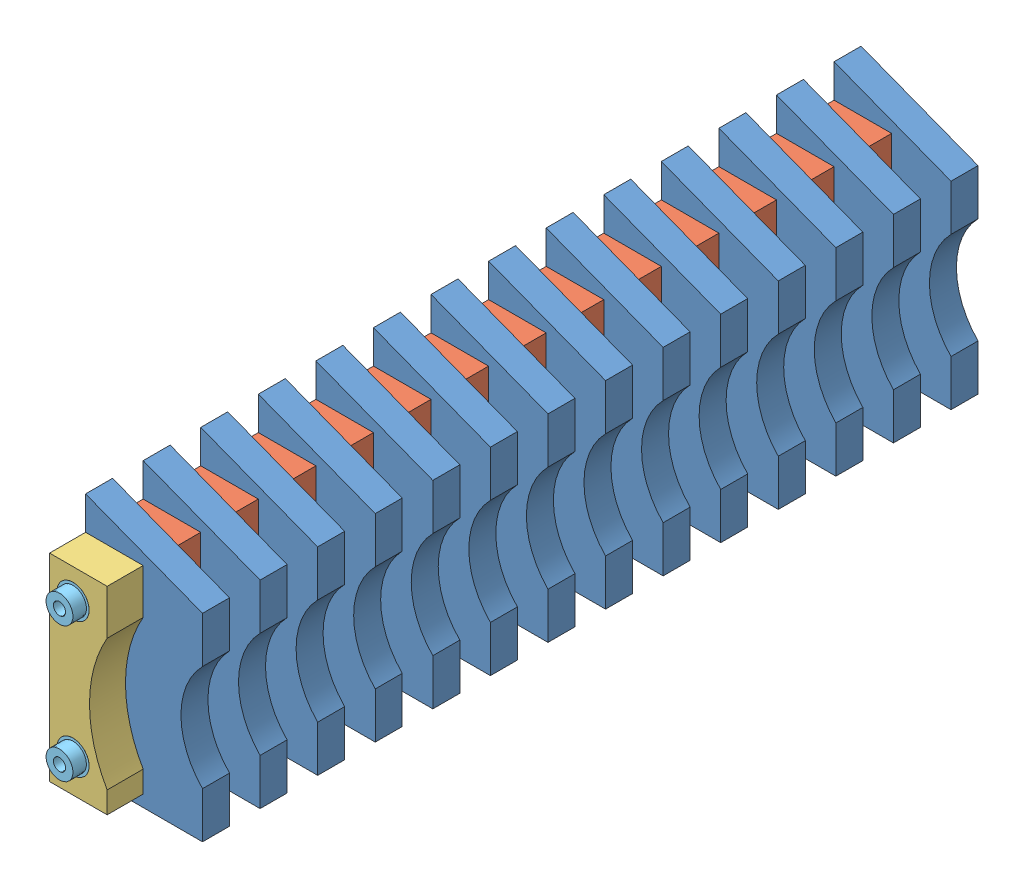
SolidWorks assembly KR.10.06, configuration Default. Lengths in mm.
Overall size (65 135 470).
31 component instances, 5 part files, 12 mates.
Components (placement in the parent):
- KR.12.04-1: KR.12.04 [Default] at (40.0493 6.8509 89.2819) size (65 135 15)
- KR.12.04-2: KR.12.04 [Default] at (40.0493 6.8509 121.2819) size (65 135 15)
- KR.12.04-3: KR.12.04 [Default] at (40.0493 6.8509 153.2819) size (65 135 15)
- KR.12.04-4: KR.12.04 [Default] at (40.0493 6.8509 185.2819) size (65 135 15)
- KR.12.04-5: KR.12.04 [Default] at (40.0493 6.8509 217.2819) size (65 135 15)
- KR.12.04-6: KR.12.04 [Default] at (40.0493 6.8509 249.2819) size (65 135 15)
- KR.12.04-7: KR.12.04 [Default] at (40.0493 6.8509 281.2819) size (65 135 15)
- KR.12.04-8: KR.12.04 [Default] at (40.0493 6.8509 313.2819) size (65 135 15)
- KR.12.04-9: KR.12.04 [Default] at (40.0493 6.8509 345.2819) size (65 135 15)
- KR.12.04-10: KR.12.04 [Default] at (40.0493 6.8509 377.2819) size (65 135 15)
- KR.12.04-11: KR.12.04 [Default] at (40.0493 6.8509 409.2819) size (65 135 15)
- KR.12.04-12: KR.12.04 [Default] at (40.0493 6.8509 441.2819) size (65 135 15)
- KR.12.04-13: KR.12.04 [Default] at (40.0493 6.8509 473.2819) size (65 135 15)
- KR.12.04-14: KR.12.04 [Default] at (40.0493 6.8509 505.2819) size (65 135 15)
- KR.13.09-1: KR.13.09 [Default] at (40.0493 13.3509 105.2819) size (32 110 17)
- KR.13.09-2: KR.13.09 [Default] at (40.0493 13.3509 137.2819) size (32 110 17)
- KR.13.09-3: KR.13.09 [Default] at (40.0493 13.3509 169.2819) size (32 110 17)
- KR.13.09-4: KR.13.09 [Default] at (40.0493 13.3509 201.2819) size (32 110 17)
- KR.13.09-5: KR.13.09 [Default] at (40.0493 13.3509 233.2819) size (32 110 17)
- KR.13.09-6: KR.13.09 [Default] at (40.0493 13.3509 265.2819) size (32 110 17)
- KR.13.09-7: KR.13.09 [Default] at (40.0493 13.3509 297.2819) size (32 110 17)
- KR.13.09-8: KR.13.09 [Default] at (40.0493 13.3509 329.2819) size (32 110 17)
- KR.13.09-9: KR.13.09 [Default] at (40.0493 13.3509 361.2819) size (32 110 17)
- KR.13.09-10: KR.13.09 [Default] at (40.0493 13.3509 393.2819) size (32 110 17)
- KR.13.09-11: KR.13.09 [Default] at (40.0493 13.3509 425.2819) size (32 110 17)
- KR.13.09-12: KR.13.09 [Default] at (40.0493 13.3509 457.2819) size (32 110 17)
- KR.13.09-13: KR.13.09 [Default] at (40.0493 13.3509 489.2819) size (32 110 17)
- KR.13.11-1: KR.13.11 [Default] at (40.0493 13.3509 522.7819) size (32 110 20)
- KR.13.12-1: KR.13.12 [Default] at (40.0493 13.3509 79.7819) size (32 110 4)
- KR.13.08-1: KR.13.08 [Default] at (53.0493 31.8509 305.2819) x (0 0 -1) z (0.733858 -0.679303 0) size (470 18 18)
- KR.13.08-2: KR.13.08 [Default] at (53.0493 106.8509 305.2819) x (0 0 -1) z (-0.134257 0.990947 0) size (470 18 18)
Mates (geometry in assembly coordinates):
- Eş Merkezli1: concentric aligned: cylinder of KR.12.04-1 through (53.0493 106.8509 81.7819) axis (0 0 1) radius 9; cylinder of KR.13.09-1 through (53.0493 106.8509 96.7819) axis (0 0 1) radius 9
- Eş Merkezli2: concentric aligned: cylinder of KR.12.04-2 through (53.0493 31.8509 113.7819) axis (0 0 1) radius 9; cylinder of KR.13.09-1 through (53.0493 31.8509 96.7819) axis (0 0 1) radius 9
- Çakışık5: coincident anti-aligned: plane of KR.12.04-1 through (135.0493 61.8509 81.7819) normal (0 0 -1); plane of KR.13.12-1 through (135.0493 61.8509 81.7819) normal (0 0 1)
- Eş Merkezli9: concentric aligned: cylinder of KR.13.12-1 through (53.0493 31.8509 77.7819) axis (0 0 1) radius 9; cylinder of KR.13.08-1 through (53.0493 31.8509 540.2819) axis (0 0 1) radius 9
- Eş Merkezli10: concentric: cylinder of KR.13.12-1 through (53.0493 106.8509 77.7819) axis (0 0 1) radius 9; cylinder of KR.13.08-2 through (53.0493 106.8509 531.4674) axis (0 0 1) radius 9
- Eş Merkezli11: concentric: cylinder of KR.12.04-1 through (53.0493 106.8509 81.7819) axis (0 0 1) radius 9; cylinder of KR.13.08-2 through (53.0493 106.8509 531.4674) axis (0 0 1) radius 9
- Eş Merkezli12: concentric aligned: cylinder of KR.12.04-1 through (53.0493 31.8509 81.7819) axis (0 0 1) radius 9; cylinder of KR.13.08-1 through (53.0493 31.8509 540.2819) axis (0 0 1) radius 9
- Çakışık6: coincident aligned: plane of KR.13.12-1 through (135.0493 61.8509 77.7819) normal (0 0 -1); plane of KR.13.08-1 through (48.1393 24.3083 77.7819) normal (0 0 -1)
- Çakışık7: coincident anti-aligned: plane of KR.12.04-14 through (135.0493 61.8509 512.7819) normal (0 0 1); plane of KR.13.11-1 through (135.0493 61.8509 512.7819) normal (0 0 -1)
- Eş Merkezli13: concentric: cylinder of KR.13.11-1 through (53.0493 106.8509 512.7819) axis (0 0 1) radius 9; cylinder of KR.13.08-2 through (53.0493 106.8509 531.4674) axis (0 0 1) radius 9
- Eş Merkezli14: concentric aligned: cylinder of KR.13.11-1 through (53.0493 31.8509 512.7819) axis (0 0 1) radius 9; cylinder of KR.13.08-1 through (53.0493 31.8509 540.2819) axis (0 0 1) radius 9
- Çakışık8: coincident aligned: plane of KR.13.12-1 through (135.0493 61.8509 77.7819) normal (0 0 -1); plane of KR.13.08-2 through (44.1308 105.6426 77.7819) normal (0 0 -1)
